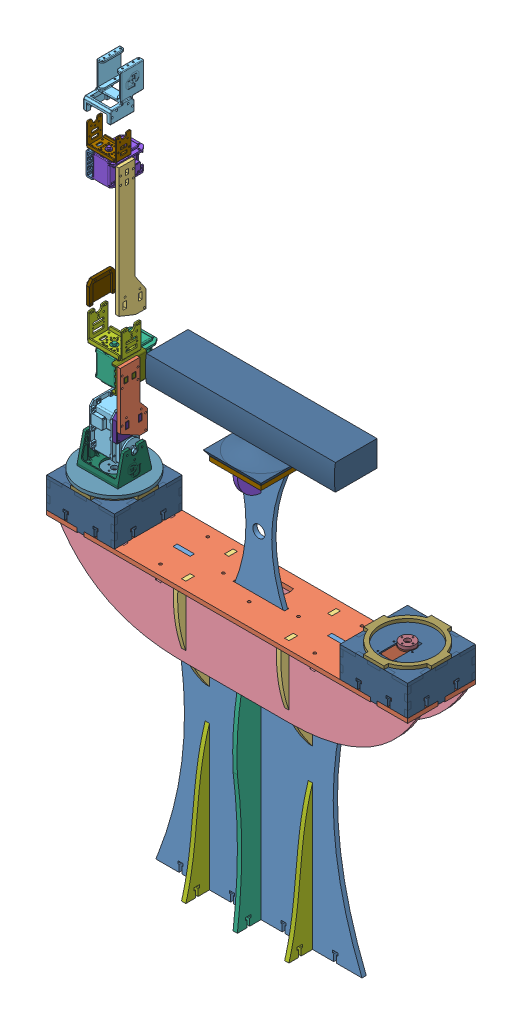
SolidWorks assembly Torso, configuration Default. Lengths in mm.
Overall size (656.71 1018.99 211.85).
72 component instances, 28 part files, 27 mates.
Components (placement in the parent):
- main-1: main [Default] at (-141.2092 -110.0105 149.2537) size (304.8 584.2 6.35)
- top-1: top [Default] at (11.1908 296.3895 152.4287) size (533.4 6.35 101.35)
- shouler-1: shouler [Default] at (-68.1842 -110.0105 149.2537) x (0 0 -1) z (1 0 0) size (101.62 152.4 6.35)
- shouler-2: shouler [Default] at (84.2158 -110.0105 149.2537) x (0 0 -1) z (1 0 0) size (101.62 152.4 6.35)
- Breast-2: Breast [Default] at (-61.108 -110.0105 184.1787) size (533.43 105.13 6.35)
- Breast-3: Breast [Default] at (-61.108 -110.0105 114.3287) size (533.43 105.13 6.35)
- Arm Assembly-1: Arm Assembly [Default] at (-205.5092 302.7395 86.5166) size (223.31 611 211.85)
  - EX-106+-2: EX-106+ [Default] at (-0.001 90.525 65.9121) x (0 0 1) z (1 0 0) size (40.2 200.67 55.3) (hidden)
  - RX-64-1: RX-64 [Default] at (-0.001 186.725 65.9121) x (-1 0 0) z (0 1 0) size (40.2 62.1 50) (hidden)
  - rx64-h101-1: rx64-h101 [Default] at (-0.001 246.2251 65.9121) x (-1 0 0) z (0 0 1) size (150 200 33) (hidden)
  - RX-64-2: RX-64 [Default] at (-0.0009 246.2251 65.9121) x (0 0 -1) z (-1 0 0) size (40.2 62.1 50) (hidden)
  - RX-28-1: RX-28 [Default] at (-0.0009 443.9251 74.0121) x (-1 0 0) z (0 1 0) size (117.84 201.45 118.07) (hidden)
  - rx28-h101-1: rx28-h101 [Default] at (-0.0009 494.4252 74.0121) x (1 0 0) z (0 0 -1) size (143.25 200 26) (hidden)
  - RX-28-3: RX-28 [Default] at (-0.0109 494.4252 74.0121) x (0 0 1) z (1 0 0) size (117.84 201.45 118.07) (hidden)
  - AX12 and Base - Test assembly-1: AX12 and Base - Test assembly [Default] at (0 0 65.9121) x (0 0 -1) z (1 0 0) size (100 54.76 100)
    - Robotic Arm Base-1: Robotic Arm Base [Default] at origin size (100 49.76 100)
    - AX-12-1: AX-12 [Default] at (0 24.2375 0) x (0 0 1) z (0 1 0) size (32 50 40.7)
    - Low-Friction Disk-1: Low-Friction Disk [Default] at (0 45 0) size (100 4.76 100)
    - Spacer Disk-1: Spacer Disk [Default] at (0 45.2375 0) size (22 4.76 22)
  - Rotating Disk-1: Rotating Disk [Default] at (0 49.7625 65.9121) size (101.6 6.35 101.6) (hidden)
  - Connector - New Disk to EX 106+-1: Connector - New Disk to EX 106+ [Default] at (0 54.525 65.9121) size (60 42 50) (hidden)
  - Custom Frame - RX 64 to Delrin Plates Upper-1: Custom Frame - RX 64 to Delrin Plates Upper [Default] at (23.999 186.725 65.9121) x (0 0 1) z (0 -1 0) size (43.6 14.06 38) (hidden)
  - Custom Frame - RX 64 to Delrin Plates Upper-2: Custom Frame - RX 64 to Delrin Plates Upper [Default] at (-24.001 186.725 65.9121) x (0 0 1) z (0 1 0) size (43.6 14.06 38) (hidden)
  - Custom Frame - EX 106 to Delrin Plates-1: Custom Frame - EX 106 to Delrin Plates [Default] at (16.999 123.425 65.9121) x (0 -1 0) z (0 0 1) size (35.4 11.76 40.2) (hidden)
  - Custom Frame - EX 106 to Delrin Plates-2: Custom Frame - EX 106 to Delrin Plates [Default] at (-17.001 123.425 65.9121) x (0 -1 0) z (0 0 -1) size (35.4 11.76 40.2) (hidden)
  - Custom Frame - RX 64 to Delrin Plates Lower-1: Custom Frame - RX 64 to Delrin Plates Lower [Default] at (-17.0009 277.8751 65.9121) x (0 -1 0) z (0 0 -1) size (32.9 9.76 40.2) (hidden)
  - Custom Frame - RX 28 to Delrin Plates Upper-1: Custom Frame - RX 28 to Delrin Plates Upper [Default] at (-21.0009 443.9251 74.0121) x (0 0 1) z (0 1 0) size (29.5 14.36 35) (hidden)
  - Custom Frame - RX 28 to Delrin Plates Upper-2: Custom Frame - RX 28 to Delrin Plates Upper [Default] at (20.9991 443.9251 74.0121) x (0 0 1) z (0 -1 0) size (29.5 14.36 35) (hidden)
  - Custom Frame - RX 64 to Delrin Plates Lower-2: Custom Frame - RX 64 to Delrin Plates Lower [Default] at (16.9991 277.8751 65.9121) x (0 -1 0) z (0 0 1) size (32.9 9.76 40.2) (hidden)
  - Connection Plate - EX-106+ to RX-64-1: Connection Plate - EX-106+ to RX-64 [Default] at (23.999 205.725 86.0121) x (0 -1 0) z (1 0 0) size (100 40.2 4.76) (hidden)
  - Connection Plate - EX-106+ to RX-64-3: Connection Plate - EX-106+ to RX-64 [Default] at (-28.7635 205.725 86.0121) x (0 -1 0) z (1 0 0) size (100 40.2 4.76) (hidden)
  - Connection Plate - RX-64 to RX-28-1: Connection Plate - RX-64 to RX-28 [Default] at (21.9991 461.4251 86.0121) x (0 -1 0) z (1 0 0) size (200 40.2 4.76) (hidden)
  - Connection Plate - RX-64 to RX-28-2: Connection Plate - RX-64 to RX-28 [Default] at (-26.7634 461.4251 86.0121) x (0 -1 0) z (1 0 0) size (200 40.2 4.76) (hidden)
  - Bushing-1: Bushing [Default] at (-31.581 90.525 65.9121) x (0 -1 0) z (0 0 1) size (10 7.08 10) (hidden)
  - AX-12-1: AX-12 [Default] at (-0.0109 554.0252 74.0121) x (-1 0 0) z (0 1 0) size (32 50 40.7) (hidden)
  - Custom Frame - RX-28 to AX-12 for Old Gripper-1: Custom Frame - RX-28 to AX-12 for Old Gripper [Default] at (14.9891 524.2252 74.0121) x (0 1 0) z (0 0 -1) size (57.6 40 51.8) (hidden)
- Arm Assembly-2: Arm Assembly [Default] at (227.8908 302.7395 86.5166) size (223.31 611 211.85)
  - EX-106+-2: EX-106+ [Default] at (-0.001 90.525 65.9121) x (0 0 1) z (1 0 0) size (40.2 200.67 55.3) (hidden)
  - RX-64-1: RX-64 [Default] at (-0.001 186.725 65.9121) x (-1 0 0) z (0 1 0) size (40.2 62.1 50) (hidden)
  - rx64-h101-1: rx64-h101 [Default] at (-0.001 246.2251 65.9121) x (-1 0 0) z (0 0 1) size (150 200 33) (hidden)
  - RX-64-2: RX-64 [Default] at (-0.0009 246.2251 65.9121) x (0 0 -1) z (-1 0 0) size (40.2 62.1 50) (hidden)
  - RX-28-1: RX-28 [Default] at (-0.0009 443.9251 74.0121) x (-1 0 0) z (0 1 0) size (117.84 201.45 118.07) (hidden)
  - rx28-h101-1: rx28-h101 [Default] at (-0.0009 494.4252 74.0121) x (1 0 0) z (0 0 -1) size (143.25 200 26) (hidden)
  - RX-28-3: RX-28 [Default] at (-0.0109 494.4252 74.0121) x (0 0 1) z (1 0 0) size (117.84 201.45 118.07) (hidden)
  - AX12 and Base - Test assembly-1: AX12 and Base - Test assembly [Default] at (0 0 65.9121) x (0 0 -1) z (1 0 0) size (100 54.76 100)
    - Robotic Arm Base-1: Robotic Arm Base [Default] at origin size (100 49.76 100)
    - AX-12-1: AX-12 [Default] at (0 24.2375 0) x (0 0 1) z (0 1 0) size (32 50 40.7)
    - Low-Friction Disk-1: Low-Friction Disk [Default] at (0 45 0) size (100 4.76 100)
    - Spacer Disk-1: Spacer Disk [Default] at (0 45.2375 0) size (22 4.76 22)
  - Rotating Disk-1: Rotating Disk [Default] at (0 49.7625 65.9121) size (101.6 6.35 101.6) (hidden)
  - Connector - New Disk to EX 106+-1: Connector - New Disk to EX 106+ [Default] at (0 54.525 65.9121) size (60 42 50) (hidden)
  - Custom Frame - RX 64 to Delrin Plates Upper-1: Custom Frame - RX 64 to Delrin Plates Upper [Default] at (23.999 186.725 65.9121) x (0 0 1) z (0 -1 0) size (43.6 14.06 38) (hidden)
  - Custom Frame - RX 64 to Delrin Plates Upper-2: Custom Frame - RX 64 to Delrin Plates Upper [Default] at (-24.001 186.725 65.9121) x (0 0 1) z (0 1 0) size (43.6 14.06 38) (hidden)
  - Custom Frame - EX 106 to Delrin Plates-1: Custom Frame - EX 106 to Delrin Plates [Default] at (16.999 123.425 65.9121) x (0 -1 0) z (0 0 1) size (35.4 11.76 40.2) (hidden)
  - Custom Frame - EX 106 to Delrin Plates-2: Custom Frame - EX 106 to Delrin Plates [Default] at (-17.001 123.425 65.9121) x (0 -1 0) z (0 0 -1) size (35.4 11.76 40.2) (hidden)
  - Custom Frame - RX 64 to Delrin Plates Lower-1: Custom Frame - RX 64 to Delrin Plates Lower [Default] at (-17.0009 277.8751 65.9121) x (0 -1 0) z (0 0 -1) size (32.9 9.76 40.2) (hidden)
  - Custom Frame - RX 28 to Delrin Plates Upper-1: Custom Frame - RX 28 to Delrin Plates Upper [Default] at (-21.0009 443.9251 74.0121) x (0 0 1) z (0 1 0) size (29.5 14.36 35) (hidden)
  - Custom Frame - RX 28 to Delrin Plates Upper-2: Custom Frame - RX 28 to Delrin Plates Upper [Default] at (20.9991 443.9251 74.0121) x (0 0 1) z (0 -1 0) size (29.5 14.36 35) (hidden)
  - Custom Frame - RX 64 to Delrin Plates Lower-2: Custom Frame - RX 64 to Delrin Plates Lower [Default] at (16.9991 277.8751 65.9121) x (0 -1 0) z (0 0 1) size (32.9 9.76 40.2) (hidden)
  - Connection Plate - EX-106+ to RX-64-1: Connection Plate - EX-106+ to RX-64 [Default] at (23.999 205.725 86.0121) x (0 -1 0) z (1 0 0) size (100 40.2 4.76) (hidden)
  - Connection Plate - EX-106+ to RX-64-3: Connection Plate - EX-106+ to RX-64 [Default] at (-28.7635 205.725 86.0121) x (0 -1 0) z (1 0 0) size (100 40.2 4.76) (hidden)
  - Connection Plate - RX-64 to RX-28-1: Connection Plate - RX-64 to RX-28 [Default] at (21.9991 461.4251 86.0121) x (0 -1 0) z (1 0 0) size (200 40.2 4.76) (hidden)
  - Connection Plate - RX-64 to RX-28-2: Connection Plate - RX-64 to RX-28 [Default] at (-26.7634 461.4251 86.0121) x (0 -1 0) z (1 0 0) size (200 40.2 4.76) (hidden)
  - Bushing-1: Bushing [Default] at (-31.581 90.525 65.9121) x (0 -1 0) z (0 0 1) size (10 7.08 10) (hidden)
  - AX-12-1: AX-12 [Default] at (-0.0109 554.0252 74.0121) x (-1 0 0) z (0 1 0) size (32 50 40.7) (hidden)
  - Custom Frame - RX-28 to AX-12 for Old Gripper-1: Custom Frame - RX-28 to AX-12 for Old Gripper [Default] at (14.9891 524.2252 74.0121) x (0 1 0) z (0 0 -1) size (57.6 40 51.8) (hidden)
- spine-1: spine [Default] at (8.0158 -110.0105 149.2537) x (0 0 -1) z (1 0 0) size (78.77 406.4 6.35)
- Hip-1: Hip [Default] at (84.2158 -110.0105 149.2537) x (0 0 -1) z (1 0 0) size (76.64 213.23 6.35)
- Hip-2: Hip [Default] at (-68.1842 -110.0105 149.2537) x (0 0 -1) z (1 0 0) size (76.64 213.23 6.35)
- chin-1: chin [Default] at (14.3658 -110.0105 149.2537) x (0 0 1) z (-1 0 0) size (76.2 37.97 6.35)
- jaw-1: jaw [Default] at (14.3658 474.1895 149.2537) x (0 0 -1) z (0 1 0) size (76.42 76.25 6.35)
- kinect-1: kinect [Default] at (11.1683 537.6895 152.3202) size (279.4 76.2 85.34)
Mates (geometry in assembly coordinates):
- InPlace1: in place: plane of main-1 through (-68.1842 220.1895 155.6037) normal (1 0 0); plane of ? through (-68.1842 0 0) normal (1 0 0); moOrthogonalPlaneRef_w of main-1 through (-68.1842 220.1895 155.6037) normal (1 0 0); line of ? through (-55 -68.1842 0) axis (0 0 1); plane of main-1 through (-68.1842 220.1895 155.6037) normal (1 0 0); plane of ? through (-68.1842 0 0) normal (0 0 -1); plane of main-1 through (-68.1842 220.1895 155.6037) normal (1 0 0); unknown of ?
- Coincident7: coincident aligned: plane of main-1; plane of shouler-1
- Coincident8: coincident aligned: moOrthogonalPlaneRef_w of main-1 through (-68.1842 -110.0105 149.2537) normal (0 1 0); plane of shouler-1
- Coincident9: coincident anti-aligned: moOrthogonalPlaneRef_w of main-1 through (-68.1842 -110.0105 149.2537) normal (0 0 1); plane of shouler-1 through (-68.1842 -110.0105 149.2537) normal (0 0 -1)
- Coincident18: coincident: point of top-1; point of Arm Assembly-1/AX12 and Base - Test assembly-1/Robotic Arm Base-1
- Perpendicular1: perpendicular: plane of top-1 through (277.8908 302.7395 102.4287) normal (0 1 0); plane of Breast-2 through (-180.1194 222.2578 190.5287) normal (0 0 1)
- Coincident20: coincident: point of top-1; point of Arm Assembly-2/AX12 and Base - Test assembly-1/Robotic Arm Base-1
- InPlace2: in place: plane of main-1 through (8.0158 42.3895 155.6037) normal (1 0 0); plane of ? through (8.0158 0 0) normal (1 0 0); plane of main-1 through (8.0158 42.3895 155.6037) normal (1 0 0); line of ? through (-55 8.0158 0) axis (0 0 1); plane of main-1 through (8.0158 42.3895 155.6037) normal (1 0 0); plane of ? through (8.0158 0 0) normal (0 0 -1); plane of main-1 through (8.0158 42.3895 155.6037) normal (1 0 0); unknown of spine-1
- Coincident21: coincident aligned: plane of main-1 through (8.0158 42.3895 155.6037) normal (1 0 0); plane of spine-1 through (8.0158 -110.0105 149.2537) normal (1 0 0)
- Coincident22: coincident aligned: moOrthogonalPlaneRef_w of main-1 through (8.0158 -110.0105 149.2537) normal (0 1 0); plane of spine-1
- Coincident23: coincident anti-aligned: moOrthogonalPlaneRef_w of main-1 through (8.0158 -110.0105 149.2537) normal (0 0 1); plane of spine-1 through (8.0158 -110.0105 149.2537) normal (0 0 -1)
- InPlace3: in place: plane of main-1 through (84.2158 -8.4105 155.6037) normal (1 0 0); plane of ? through (84.2158 0 0) normal (1 0 0); plane of main-1 through (84.2158 -8.4105 155.6037) normal (1 0 0); line of ? through (-55 84.2158 0) axis (0 0 1); plane of main-1 through (84.2158 -8.4105 155.6037) normal (1 0 0); plane of ? through (84.2158 0 0) normal (0 0 -1); plane of main-1 through (84.2158 -8.4105 155.6037) normal (1 0 0); unknown of ?
- Coincident24: coincident aligned: plane of main-1; plane of Hip-1
- Coincident25: coincident aligned: moOrthogonalPlaneRef_w of main-1 through (84.2158 -110.0105 149.2537) normal (0 1 0); plane of Hip-1
- Coincident26: coincident anti-aligned: moOrthogonalPlaneRef_w of main-1 through (84.2158 -110.0105 149.2537) normal (0 0 1); plane of Hip-1 through (84.2158 -110.0105 149.2537) normal (0 0 -1)
- Coincident31: coincident: point of main-1; point of Hip-2
- Coincident32: coincident: plane of main-1 through (-98.7412 96.0489 155.6037) normal (0 0 1); point of Hip-2
- Perpendicular5: perpendicular: plane of main-1 through (-98.7412 96.0489 149.2537) normal (0 0 -1); plane of Hip-2 through (-68.1842 -3.2595 173.7094) normal (-1 0 0)
- Coincident34: coincident aligned: line of main-1 through (-68.1842 -110.0105 155.6037) axis (0 0 -1); line of Hip-2 through (-68.1842 -110.0105 190.5287) axis (0 0 -1)
- InPlace4: in place: plane of main-1 through (14.3658 448.7895 155.6037) normal (-1 0 0); plane of ? through (14.3658 0 0) normal (-1 0 0); plane of main-1 through (14.3658 448.7895 155.6037) normal (-1 0 0); line of ? through (-55 14.3658 0) axis (0 0 1); plane of main-1 through (14.3658 448.7895 155.6037) normal (-1 0 0); plane of ? through (14.3658 0 0) normal (0 0 1); plane of main-1 through (14.3658 448.7895 155.6037) normal (-1 0 0); unknown of chin-1
- Coincident35: coincident aligned: plane of main-1; plane of chin-1
- Coincident36: coincident aligned: moOrthogonalPlaneRef_w of main-1 through (14.3658 -110.0105 149.2537) normal (0 1 0); plane of chin-1
- Coincident37: coincident anti-aligned: moOrthogonalPlaneRef_w of main-1 through (14.3658 -110.0105 149.2537) normal (0 0 -1); plane of chin-1 through (14.3658 -110.0105 149.2537) normal (0 0 1)
- InPlace5: in place: plane of chin-1 through (8.0158 474.1895 152.4287) normal (0 1 0); plane of ? through (0 474.1895 0) normal (0 1 0); plane of chin-1 through (8.0158 474.1895 152.4287) normal (0 1 0); line of ? through (-55 0 474.1895) axis (0 -1 0); plane of chin-1 through (8.0158 474.1895 152.4287) normal (0 1 0); unknown of ?; plane of chin-1 through (8.0158 474.1895 152.4287) normal (0 1 0); unknown of jaw-1
- Coincident38: coincident aligned: plane of chin-1; plane of jaw-1
- Coincident39: coincident aligned: moOrthogonalPlaneRef_w of chin-1 through (14.3658 474.1895 149.2537) normal (-1 0 0); plane of jaw-1
- Coincident40: coincident anti-aligned: moOrthogonalPlaneRef_w of chin-1 through (14.3658 474.1895 149.2537) normal (0 0 1); plane of top-1
